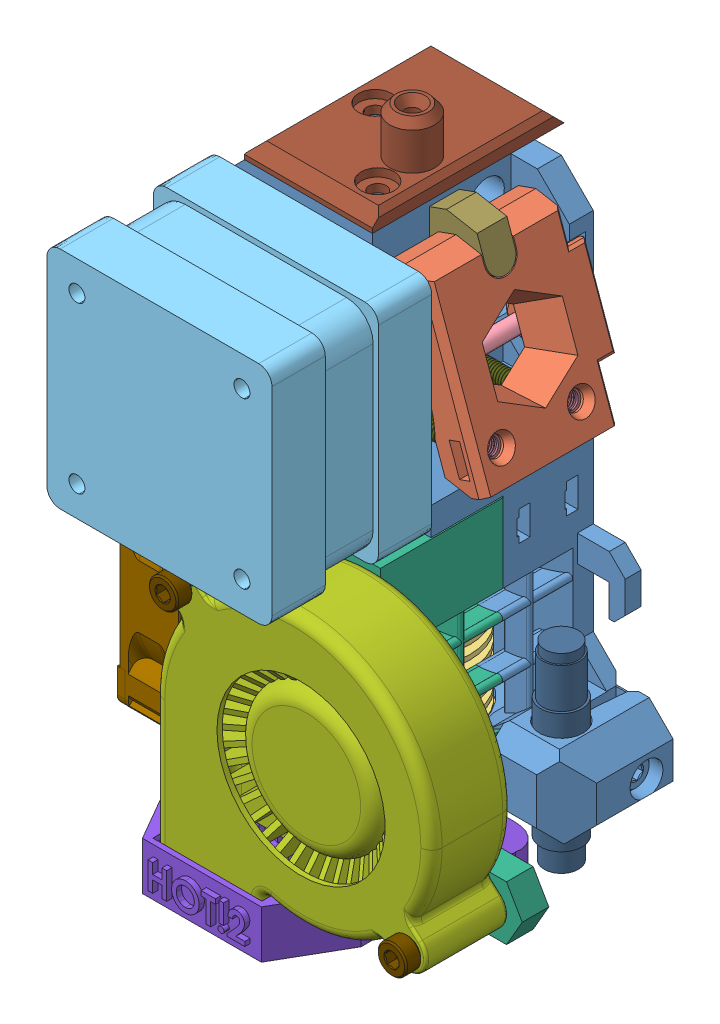
SolidWorks assembly Extruder Assembly, configuration Default. Lengths in mm.
Overall size (76.41 114.5 66).
35 component instances, 19 part files, 84 mates.
Components (placement in the parent):
- extruder-body-1: extruder-body [Default] at (24.1066 59.0375 55.4042) x (-1 0 0) z (0 0 -1) size (63.5 95 30.5)
- extruder-idler-1: extruder-idler [Default] at (39.0743 57.6459 53.9042) x (0 0 -1) z (0.941715 0.336411 0) size (28 34 17)
- E3D V6-1: E3D V6 [Default] at (24.1066 48.6175 72.4042) x (1 0 0) z (0 -1 0) size (21.69 25.84 58.6)
- idler pulley shaft-1: idler pulley shaft [Default] at (33.7581 84.4179 56.6542) x (-0.93241 -0.361403 0) z (0 0 1) size (3 3 24)
- MOTOR_NEMA17_30MM-1: MOTOR_NEMA17_30MM [Default] at (20.1066 86.0375 100.9042) x (0 -1 0) z (0 0 -1) size (54.71 42.3 52)
- extruder-cover-1: extruder-cover [Default] at (24.1066 59.0375 55.4042) x (-1 0 0) z (0 0 -1) size (75.15 49.75 23.94)
- FAN_5015_BLOWER-1: FAN_5015_BLOWER [Default] at (41.6066 38.5375 110.8042) x (0 -1 0) z (1 0 0) size (51.75 17.19 52.1)
- nozzle-fan-1: nozzle-fan [Default] at (24.1066 59.0375 59.9042) x (-1 0 0) z (0 0 -1) size (47.83 17 42)
- Noctua-NF-A4x10-1: Noctua-NF-A4x10 [Default] at (-2.3925 37.472 75.3387) x (0 0 -1) z (-1 0 0) size (40.06 40.06 12.26)
- PINDA Probe-1: PINDA Probe [Default] at (47.1066 30.9837 67.4042) x (0.998123 0 0.061245) z (0 -1 0) size (7.8 7.8 35.75)
- filament-sensor-cover-1: filament-sensor-cover [Default] at (24.1066 59.0375 55.4042) x (-1 0 0) z (0 0 -1) size (24 11.5 36)
- extruder-idler-plug-1: extruder-idler-plug [Default] at (39.0743 57.6459 53.9042) x (-0.941715 -0.336411 0) z (0 0 -1) size (10.6 10.3 5.6)
- M3 Square Nut-1: M3 Square Nut [Default] at (44.9988 79.4073 80.4042) x (-0.336411 0.941715 0) z (0.941715 0.336411 0) size (5.5 5.5 1.97)
- M3 Square Nut-2: M3 Square Nut [Default] at (44.9988 79.4073 65.4042) x (-0.336411 0.941715 0) z (0.941715 0.336411 0) size (5.5 5.5 1.97)
- M3 Hex Nut-1: M3 Hex Nut [Default] at (12.6066 58.5375 67.6042) x (0.866025 0.5 0) z (0 0 1) size (5.5 6.35 2.74)
- M3 Hex Nut-2: M3 Hex Nut [Default] at (7.1066 62.0375 66.7042) x (0.866025 0.5 0) z (0 0 1) size (5.5 6.35 2.74)
- M3-30 Screw-1: M3-30 Screw [91292A022] at (35.6066 101.5375 88.4042) x (0.835728 0.549143 0) z (0 0 1) size (5.5 5.5 33.26)
- M3-30 Screw-2: M3-30 Screw [91292A022] at (35.6066 70.5375 89.1542) x (0.782699 -0.622401 0) z (0 0 1) size (5.5 5.5 33.26)
- M3-30 Screw-3: M3-30 Screw [91292A022] at (4.6066 70.5375 89.1542) x (0.814123 -0.580692 0) z (0 0 1) size (5.5 5.5 33.26)
- M3-40 Screw-1: M3-40 Screw [91292A024] at (42.1066 77.5375 65.4042) x (0 0 -1) z (1 0 0) size (5.5 5.5 43.26)
- M3-40 Screw-2: M3-40 Screw [91292A024] at (42.1066 77.5375 80.4042) x (0 0 -1) z (1 0 0) size (5.5 5.5 43.26)
- M3 Square Nut-3: M3 Square Nut [Default] at (35.6066 58.5375 67.3042) size (5.5 5.5 1.97)
- M3 Square Nut-4: M3 Square Nut [Default] at (35.6066 58.5375 58.3042) size (5.5 5.5 1.97)
- M3 Hex Nut-3: M3 Hex Nut [Default] at (61.8566 20.5375 93.6042) x (0.866025 0.5 0) z (0 0 1) size (5.5 6.35 2.74)
- M3 Square Nut-5: M3 Square Nut [Default] at (18.6066 58.5375 92.6042) size (5.5 5.5 1.97)
- M3-25 Screw-1: M3-25 Screw [91292A020] at (35.6066 58.5375 65.9042) x (-1 0 0) z (0 0 -1) size (5.5 5.5 28.26)
- M3-25 Screw-2: M3-25 Screw [91292A020] at (7.1066 62.0375 62.4042) x (-1 0 0) z (0 0 -1) size (5.5 5.5 28.26)
- M3-18 Screw-1: M3-18 Screw [91292A029] at (13.0294 21.4065 59.2732) x (0 -1 0.000168) z (1 0 0) size (5.5 5.5 21.26)
- M3-18 Screw-2: M3-18 Screw [91292A029] at (61.6066 20.5375 92.8042) x (-0.923728 -0.383049 0) z (0 0 -1) size (5.5 5.5 21.26)
- M3-18 Screw-3: M3-18 Screw [91292A029] at (18.6066 58.5375 92.8042) x (-1 0 0) z (0 0 -1) size (5.5 5.5 21.26)
- M3-18 Screw-4: M3-18 Screw [91292A029] at (13.0294 21.4065 91.4042) x (0 0.010223 -0.999948) z (1 0 0) size (5.5 5.5 21.26)
- M3-18 Screw-5: M3-18 Screw [91292A029] at (13.0294 53.5375 91.4042) x (0 -0.071429 -0.997446) z (1 0 0) size (5.5 5.5 21.26)
- M3-18 Screw-6: M3-18 Screw [91292A029] at (13.0294 53.5375 59.2732) x (0 0.473928 -0.880563) z (1 0 0) size (5.5 5.5 21.26)
- M3 Square Nut-6: M3 Square Nut [Default] at (41.3066 20.5375 60.4042) x (0 0 -1) z (1 0 0) size (5.5 5.5 1.97)
- M3-10 Screw-1: M3-10 Screw [93235A313] at (41.1066 20.5375 60.4042) x (0 0.744189 0.667969) z (-1 0 0) size (5.5 5.5 13.21)
Mates (geometry in assembly coordinates):
- Concentric1: concentric aligned: cylinder of extruder-body-1 through (35.6066 101.5375 58.1042) axis (0 0 -1) radius 3.1; cylinder of extruder-idler-1 through (35.6066 101.5375 85.9042) axis (0 0 -1) radius 1.7
- Concentric2: concentric aligned: cylinder of extruder-body-1 through (24.1066 63.0375 72.4042) axis (0 -1 0) radius 6.05; cylinder of E3D V6-1 through (24.1066 48.6175 72.4042) axis (0 -1 0) radius 5.95
- Distance1: distance = 1.7 mm anti-aligned: plane of E3D V6-1 through (16.2066 61.2375 72.4042) normal (0 -1 0); plane of extruder-body-1 through (24.1066 59.5375 72.4042) normal (0 1 0)
- Parallel1: parallel aligned: plane of extruder-body-1 through (3.6066 56.5375 80.4042) normal (-1 0 0); plane of E3D V6-1 through (16.6066 8.4175 77.4042) normal (-1 0 0)
- Concentric3: concentric aligned: cylinder of extruder-idler-1 through (33.7581 84.4179 85.9042) axis (0 0 -1) radius 1.5; cylinder of idler pulley shaft-1 through (33.7581 84.4179 80.6542) axis (0 0 -1) radius 1.5
- Coincident1: coincident aligned: plane of extruder-idler-1 through (23.3992 80.7173 80.6542) normal (0 0 1); plane of idler pulley shaft-1 through (33.7581 84.4179 80.6542) normal (0 0 1)
- Concentric5: concentric aligned: cylinder of extruder-body-1 through (35.6066 70.5375 95.4042) axis (0 0 -1) radius 1.7; cylinder of MOTOR_NEMA17_30MM-1 through (35.6066 70.5375 85.9042) axis (0 0 -1) radius 1.5
- Concentric6: concentric aligned: cylinder of extruder-body-1 through (4.6066 70.5375 95.4042) axis (0 0 -1) radius 1.7; cylinder of MOTOR_NEMA17_30MM-1 through (4.6066 70.5375 85.9042) axis (0 0 -1) radius 1.5
- Coincident2: coincident anti-aligned: plane of extruder-body-1 through (41.1066 22.5375 85.9042) normal (0 0 1); plane of MOTOR_NEMA17_30MM-1 through (20.1066 86.0375 85.9042) normal (0 0 -1)
- Coincident3: coincident anti-aligned: plane of extruder-body-1 through (42.1066 20.0375 72.4042) normal (0 0 1); plane of extruder-cover-1 through (41.1066 22.5375 72.4042) normal (0 0 -1)
- Concentric7: concentric aligned: cylinder of E3D V6-1 through (24.1066 48.6175 72.4042) axis (0 -1 0) radius 5.95; cylinder of extruder-cover-1 through (24.1066 63.0375 72.4042) axis (0 -1 0) radius 6.05
- Coincident4: coincident aligned: plane of extruder-body-1 through (34.1066 24.0375 95.9542) normal (0 1 0); plane of extruder-cover-1 through (41.3066 24.0375 91.4042) normal (0 1 0)
- Coincident6: coincident anti-aligned: plane of extruder-cover-1 through (41.1066 22.5375 95.4042) normal (0 0 1); plane of FAN_5015_BLOWER-1 through (41.6066 38.5375 95.4042) normal (0 0 -1)
- Parallel3: parallel aligned: plane of extruder-cover-1 through (8.6066 15.0375 95.4042) normal (0 -1 0); plane of FAN_5015_BLOWER-1 through (34.2066 12.8375 110.8042) normal (0 -1 0)
- Coincident7: coincident anti-aligned: plane of extruder-cover-1 through (41.1066 22.5375 95.4042) normal (0 0 1); plane of nozzle-fan-1 through (13.6066 6.0375 95.4042) normal (0 0 -1)
- Concentric11: concentric aligned: circle of extruder-cover-1; circle of nozzle-fan-1
- Parallel4: parallel anti-aligned: plane of extruder-cover-1 through (8.6066 15.0375 95.4042) normal (0 -1 0); plane of nozzle-fan-1 through (13.6066 23.0375 100.4042) normal (0 1 0)
- Concentric13: concentric anti-aligned: circle of extruder-cover-1; cylinder of FAN_5015_BLOWER-1 through (18.6066 58.5375 110.8042) axis (0 0 -1) radius 2.25
- Coincident8: coincident anti-aligned: plane of extruder-cover-1 through (3.6066 21.5375 96.4042) normal (-1 0 0); plane of Noctua-NF-A4x10-1 through (3.6066 55.4999 93.3666) normal (1 0 0)
- Concentric17: concentric anti-aligned: cylinder of extruder-cover-1 through (17.1066 53.5375 91.4042) axis (-1 0 0) radius 1.4; cylinder of Noctua-NF-A4x10-1 through (-7.8916 53.5375 91.4042) axis (1 0 0) radius 2.159
- Parallel5: parallel aligned: plane of extruder-body-1 through (8.6066 15.0375 72.4042) normal (0 -1 0); plane of Noctua-NF-A4x10-1 through (-7.8916 17.4441 93.3666) normal (0 -1 0)
- Concentric18: concentric anti-aligned: cylinder of extruder-body-1 through (47.1066 54.0375 67.4042) axis (0 -1 0) radius 4.1; cylinder of PINDA Probe-1 through (47.1066 45.0027 67.4042) axis (0 1 0) radius 3.9
- Coincident9: coincident aligned: plane of E3D V6-1 through (24.1066 6.4175 72.4042) normal (0 -1 0); plane of PINDA Probe-1 through (47.1066 6.4175 67.4042) normal (0 -1 0)
- Coincident10: coincident anti-aligned: plane of extruder-body-1 through (41.1066 109.0375 85.9042) normal (0 1 0); plane of filament-sensor-cover-1 through (30.1066 109.0375 85.9042) normal (0 -1 0)
- Concentric19: concentric aligned: cylinder of extruder-body-1 through (24.1066 109.5375 72.4042) axis (0 -1 0) radius 2.1; cylinder of filament-sensor-cover-1 through (24.1066 118.8375 72.4042) axis (0 -1 0) radius 2.2
- Concentric20: concentric aligned: cone of extruder-body-1 through (25.1066 109.0375 79.9042) axis (0 -1 0); cylinder of filament-sensor-cover-1 through (25.1066 113.5375 79.9042) axis (0 -1 0) radius 3.1
- Distance2: distance = 0.5 mm anti-aligned: plane of extruder-idler-1 through (51.0465 74.6655 60.4042) normal (0 0 -1); plane of extruder-body-1 through (50.1066 88.0375 59.9042) normal (0 0 1)
- Concentric21: concentric aligned: cylinder of extruder-idler-1 through (35.6066 101.5375 85.9042) axis (0 0 -1) radius 1.7; cylinder of extruder-idler-plug-1 through (35.6066 101.5375 85.9042) axis (0 0 -1) radius 1.5
- Concentric22: concentric aligned: cylinder of extruder-idler-1 through (43.443 104.8679 72.4042) axis (-0.941715 -0.336411 0) radius 3; cylinder of extruder-idler-plug-1 through (40.6178 103.8586 72.4042) axis (-0.941715 -0.336411 0) radius 2.8
- Concentric23: concentric aligned: circle of extruder-idler-1; circle of M3 Square Nut-2
- Parallel6: parallel aligned: plane of extruder-idler-1 through (51.6518 75.9436 86.9042) normal (0.336411 -0.941715 0); plane of M3 Square Nut-2 through (47.619 77.4231 62.6542) normal (0.336411 -0.941715 0)
- Coincident12: coincident anti-aligned: plane of extruder-idler-1 through (45.9744 76.6764 68.5042) normal (0.941715 0.336411 0); plane of M3 Square Nut-2 through (44.9988 79.4073 65.4042) normal (-0.941715 -0.336411 0)
- Concentric24: concentric aligned: circle of extruder-idler-1; circle of M3 Square Nut-1
- Coincident13: coincident anti-aligned: plane of extruder-idler-1 through (45.9744 76.6764 93.3042) normal (0.941715 0.336411 0); plane of M3 Square Nut-1 through (44.9988 79.4073 80.4042) normal (-0.941715 -0.336411 0)
- Parallel7: parallel aligned: plane of extruder-idler-1 through (35.6066 101.5375 85.4042) normal (0 0 1); plane of M3 Square Nut-1 through (45.7688 82.6026 83.1542) normal (0 0 1)
- Concentric25: concentric aligned: cylinder of extruder-body-1 through (12.6066 58.5375 85.4042) axis (0 0 -1) radius 1.7; circle of M3 Hex Nut-1
- Coincident15: coincident anti-aligned: plane of extruder-body-1 through (9.5066 58.5375 66.4042) normal (0 0 1); plane of M3 Hex Nut-1 through (12.6066 58.5375 66.4042) normal (0 0 -1)
- Parallel8: parallel anti-aligned: plane of extruder-body-1 through (14.3566 61.5686 76.4042) normal (-0.866025 -0.5 0); plane of M3 Hex Nut-1 through (14.1943 61.2875 68.8042) normal (0.866025 0.5 0)
- Concentric26: concentric anti-aligned: circle of extruder-body-1; circle of M3 Hex Nut-2
- Coincident17: coincident anti-aligned: plane of extruder-body-1 through (4.0066 62.0375 67.9042) normal (0 0 -1); plane of M3 Hex Nut-2 through (7.1066 62.0375 67.9042) normal (0 0 1)
- Parallel11: parallel anti-aligned: plane of extruder-body-1 through (10.2066 62.0375 67.9042) normal (-0.866025 0.5 0); plane of M3 Hex Nut-2 through (8.6943 59.2875 67.9042) normal (0.866025 -0.5 0)
- Concentric27: concentric anti-aligned: cylinder of extruder-body-1 through (35.6066 101.5375 58.1042) axis (0 0 -1) radius 3.1; cylinder of M3-30 Screw-1 through (35.6066 101.5375 55.4042) axis (0 0 1) radius 2.75
- Coincident20: coincident anti-aligned: plane of extruder-body-1 through (35.6066 101.5375 58.4042) normal (0 0 -1); plane of M3-30 Screw-1 through (35.6066 101.5375 58.4042) normal (0 0 1)
- Concentric28: concentric anti-aligned: cylinder of extruder-body-1 through (35.6066 70.5375 95.4042) axis (0 0 -1) radius 1.7; cylinder of M3-30 Screw-2 through (35.6066 70.5375 56.1542) axis (0 0 1) radius 2.75
- Concentric29: concentric anti-aligned: cylinder of extruder-body-1 through (4.6066 70.5375 95.4042) axis (0 0 -1) radius 1.7; cylinder of M3-30 Screw-3 through (4.6066 70.5375 56.1542) axis (0 0 1) radius 2.75
- Coincident21: coincident anti-aligned: plane of extruder-body-1 through (35.6066 70.5375 59.1542) normal (0 0 -1); plane of M3-30 Screw-2 through (35.6066 70.5375 59.1542) normal (0 0 1)
- Coincident22: coincident anti-aligned: plane of extruder-body-1 through (4.6066 70.5375 59.1542) normal (0 0 -1); plane of M3-30 Screw-3 through (4.6066 70.5375 59.1542) normal (0 0 1)
- Concentric30: concentric anti-aligned: circle of extruder-body-1; cylinder of M3-40 Screw-1 through (2.1066 77.5375 65.4042) axis (1 0 0) radius 1.5
- Concentric31: concentric anti-aligned: circle of extruder-body-1; cylinder of M3-40 Screw-2 through (2.1066 77.5375 80.4042) axis (1 0 0) radius 1.5
- Coincident23: coincident aligned: plane of extruder-body-1 through (-0.8934 22.5375 85.9042) normal (-1 0 0); plane of M3-40 Screw-1 through (-0.8934 77.5375 65.4042) normal (-1 0 0)
- Coincident24: coincident aligned: plane of extruder-body-1 through (-0.8934 22.5375 85.9042) normal (-1 0 0); plane of M3-40 Screw-2 through (-0.8934 77.5375 80.4042) normal (-1 0 0)
- Concentric32: concentric anti-aligned: cylinder of extruder-body-1 through (35.6066 58.5375 90.4042) axis (0 0 -1) radius 1.7; circle of M3 Square Nut-3
- Coincident25: coincident anti-aligned: plane of extruder-body-1 through (44.6066 55.8375 67.3042) normal (0 0 1); plane of M3 Square Nut-3 through (35.6066 58.5375 67.3042) normal (0 0 -1)
- Parallel12: parallel aligned: plane of extruder-body-1 through (41.1066 22.5375 85.9042) normal (1 0 0); plane of M3 Square Nut-3 through (38.3566 55.7875 69.1042) normal (1 0 0)
- Concentric33: concentric aligned: circle of extruder-body-1; circle of M3 Square Nut-4
- Coincident27: coincident anti-aligned: plane of extruder-body-1 through (44.6066 55.8375 58.3042) normal (0 0 1); plane of M3 Square Nut-4 through (35.6066 58.5375 58.3042) normal (0 0 -1)
- Parallel13: parallel aligned: plane of extruder-body-1 through (41.1066 22.5375 85.9042) normal (1 0 0); plane of M3 Square Nut-4 through (38.3566 55.7875 60.1042) normal (1 0 0)
- Concentric34: concentric aligned: circle of extruder-cover-1; circle of M3 Hex Nut-3
- Coincident30: coincident anti-aligned: plane of extruder-cover-1 through (58.6566 20.5375 94.8042) normal (0 0 -1); plane of M3 Hex Nut-3 through (61.8566 20.5375 94.8042) normal (0 0 1)
- Parallel14: parallel anti-aligned: plane of extruder-cover-1 through (60.2566 17.7662 94.8042) normal (0.866025 0.5 0); plane of M3 Hex Nut-3 through (58.6811 20.5375 94.8042) normal (-0.866025 -0.5 0)
- Concentric35: concentric aligned: circle of extruder-cover-1; circle of M3 Square Nut-5
- Coincident34: coincident anti-aligned: plane of extruder-cover-1 through (21.3066 55.0375 94.4042) normal (0 0 -1); plane of M3 Square Nut-5 through (18.6066 58.5375 94.4042) normal (0 0 1)
- Parallel15: parallel aligned: plane of extruder-cover-1 through (41.1066 64.7875 95.4042) normal (0 1 0); plane of M3 Square Nut-5 through (21.3566 61.2875 94.4042) normal (0 1 0)
- Concentric36: concentric aligned: cylinder of extruder-cover-1 through (7.1066 62.0375 99.4042) axis (0 0 -1) radius 1.6; cylinder of M3-25 Screw-2 through (7.1066 62.0375 90.4042) axis (0 0 -1) radius 2.75
- Concentric37: concentric aligned: cylinder of extruder-cover-1 through (35.6066 58.5375 98.4042) axis (0 0 -1) radius 1.7; cylinder of M3-25 Screw-1 through (35.6066 58.5375 93.9042) axis (0 0 -1) radius 2.75
- Coincident36: coincident anti-aligned: plane of extruder-cover-1 through (10.2066 62.1375 87.4042) normal (0 0 1); plane of M3-25 Screw-2 through (7.1066 62.0375 87.4042) normal (0 0 -1)
- Coincident37: coincident anti-aligned: plane of extruder-cover-1 through (35.6066 58.5375 90.9042) normal (0 0 1); plane of M3-25 Screw-1 through (35.6066 58.5375 90.9042) normal (0 0 -1)
- Concentric38: concentric: cylinder of Noctua-NF-A4x10-1 through (-7.8916 53.5375 91.4042) axis (1 0 0) radius 2.159; cylinder of M3-18 Screw-5 through (-7.9706 53.5375 91.4042) axis (1 0 0) radius 2.75
- Concentric39: concentric: cylinder of Noctua-NF-A4x10-1 through (-7.8916 53.5375 59.2732) axis (1 0 0) radius 2.159; cylinder of M3-18 Screw-6 through (-7.9706 53.5375 59.2732) axis (1 0 0) radius 2.75
- Concentric40: concentric: cylinder of Noctua-NF-A4x10-1 through (-7.8916 21.4065 59.2732) axis (1 0 0) radius 2.159; cylinder of M3-18 Screw-1 through (-7.9706 21.4065 59.2732) axis (1 0 0) radius 2.75
- Concentric41: concentric: circle of Noctua-NF-A4x10-1; cylinder of M3-18 Screw-4 through (-7.9706 21.4065 91.4042) axis (1 0 0) radius 2.75
- Concentric42: concentric anti-aligned: circle of FAN_5015_BLOWER-1; cylinder of M3-18 Screw-3 through (18.6066 58.5375 113.8042) axis (0 0 -1) radius 2.75
- Concentric43: concentric aligned: cylinder of FAN_5015_BLOWER-1 through (61.6066 20.5375 110.8042) axis (0 0 -1) radius 2.25; cylinder of M3-18 Screw-2 through (61.6066 20.5375 113.8042) axis (0 0 -1) radius 2.75
- Coincident38: coincident anti-aligned: plane of FAN_5015_BLOWER-1 through (41.6066 38.5375 110.8042) normal (0 0 1); plane of M3-18 Screw-2 through (61.6066 20.5375 110.8042) normal (0 0 -1)
- Coincident39: coincident anti-aligned: plane of FAN_5015_BLOWER-1 through (41.6066 38.5375 110.8042) normal (0 0 1); circle of M3-18 Screw-3
- Coincident43: coincident anti-aligned: plane of Noctua-NF-A4x10-1 through (-4.9706 53.5375 59.2732) normal (-1 0 0); plane of M3-18 Screw-6 through (-4.9706 53.5375 59.2732) normal (1 0 0)
- Coincident44: coincident anti-aligned: plane of Noctua-NF-A4x10-1 through (-4.9706 21.4065 59.2732) normal (-1 0 0); plane of M3-18 Screw-1 through (-4.9706 21.4065 59.2732) normal (1 0 0)
- Coincident45: coincident anti-aligned: plane of Noctua-NF-A4x10-1 through (-4.9706 21.4065 91.4042) normal (-1 0 0); plane of M3-18 Screw-4 through (-4.9706 21.4065 91.4042) normal (1 0 0)
- Coincident46: coincident anti-aligned: plane of Noctua-NF-A4x10-1 through (-4.9706 53.5375 91.4042) normal (-1 0 0); plane of M3-18 Screw-5 through (-4.9706 53.5375 91.4042) normal (1 0 0)
- Concentric44: concentric: cylinder of extruder-body-1 through (59.1066 20.5375 60.4042) axis (-1 0 0) radius 1.7; circle of M3 Square Nut-6
- Coincident47: coincident: plane of extruder-body-1 through (41.3066 17.5375 63.5042) normal (1 0 0); plane of M3 Square Nut-6 through (41.3066 20.5375 60.4042) normal (-1 0 0)
- Parallel16: parallel aligned: plane of extruder-body-1 through (41.1066 22.5375 55.4042) normal (0 0 -1); plane of M3 Square Nut-6 through (43.1066 17.7875 57.6542) normal (0 0 -1)
- Concentric45: concentric: cylinder of extruder-body-1 through (57.1066 20.5375 60.4042) axis (-1 0 0) radius 3.1; cylinder of M3-10 Screw-1 through (82.8821 20.5375 60.4042) axis (-1 0 0) radius 2.75
- Coincident49: coincident anti-aligned: plane of extruder-body-1 through (51.1066 20.5375 60.4042) normal (1 0 0); plane of M3-10 Screw-1 through (51.1066 20.5375 60.4042) normal (-1 0 0)
